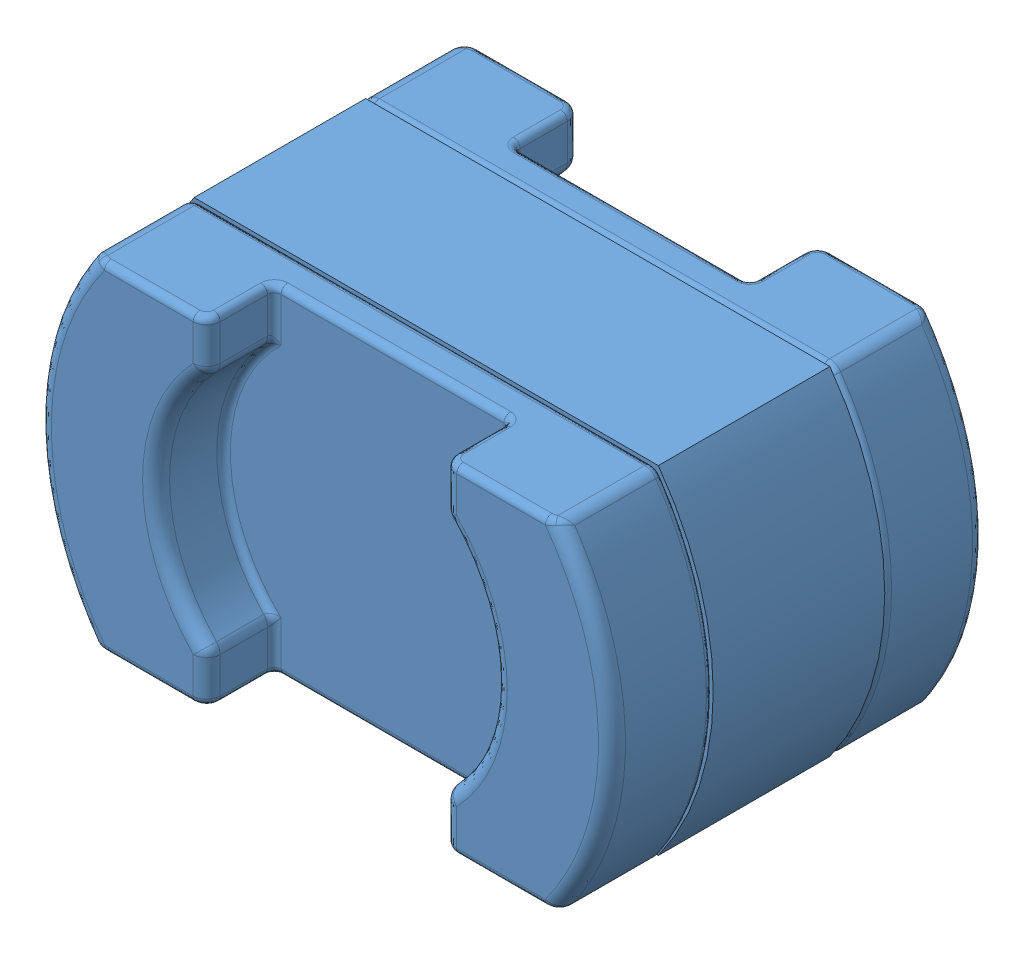
SolidWorks assembly Assem1, configuration Default. Lengths in mm.
Overall size (85 50 55.74).
3 component instances, 1 part files, 6 mates.
Components (placement in the parent):
- insert-1: insert [Default] at (0 0 -15) size (85 50 15.17)
- insert-2: insert [Default] at (0 0 40.4) x (-1 0 0) z (0 0 -1) size (85 50 15.17)
- insert-3: insert [foam] at origin size (85 50 25.4)
Mates (geometry in assembly coordinates):
- Coincident1: coincident anti-aligned: plane of insert-2 through (0 0 25.4) normal (0 0 -1); plane of insert-3 through (0 0 25.4) normal (0 0 1)
- Coincident2: coincident aligned: plane of insert-2 through (34.3693 25 25.4) normal (0 1 0); plane of insert-3 through (-34.3693 25 25.4) normal (0 1 0)
- Concentric1: concentric anti-aligned: cylinder of insert-2 through (0 0 25.4) axis (0 0 1) radius 42.5; cylinder of insert-3 through (0 0 25.4) axis (0 0 -1) radius 42.5
- Concentric2: concentric aligned: cylinder of insert-1 through (0 0 0) axis (0 0 -1) radius 42.5; cylinder of insert-3 through (0 0 25.4) axis (0 0 -1) radius 42.5
- Coincident3: coincident anti-aligned: plane of insert-1 through (0 0 0) normal (0 0 1); plane of insert-3 through (0 0 0) normal (0 0 -1)
- Coincident4: coordinate: point of insert-3
